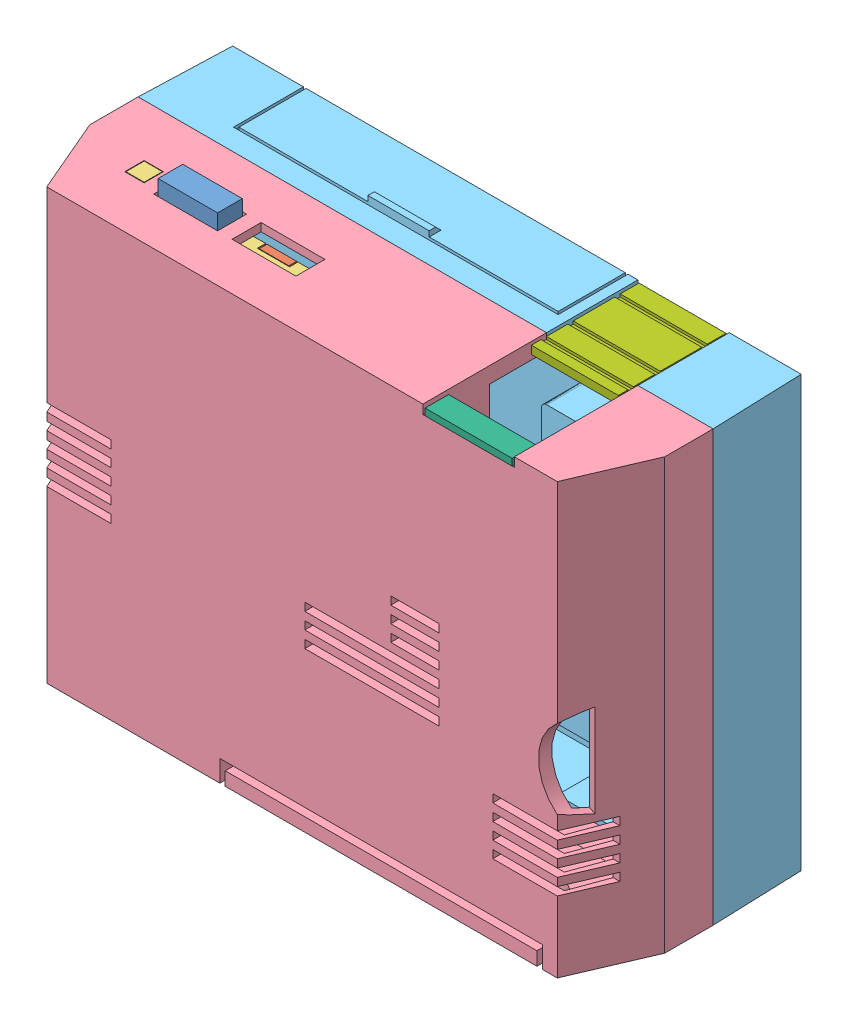
SolidWorks assembly NES_Case_Assembly, configuration Default. Lengths in mm.
Overall size (107 82.5 40).
8 component instances, 8 part files, 21 mates.
Components (placement in the parent):
- NES_Button-1: NES_Button [Default] at (-10.9151 -3.3126 23.1035) size (12.88 5 6.4)
- NES_Switch_Back-1: NES_Switch_Back [Default] at (15.7149 -17.9426 11.9035) x (-1 0 0) z (0 0 -1) size (35.58 8.88 18)
- NES_Switch_Holder-1: NES_Switch_Holder [Default] at (-9.9751 -2.3126 29.9035) x (0 -1 0) z (1 0 0) size (14.63 18 35.58)
- NES_bottom-1: NES_bottom [Default] at (19.7831 -80.8126 42.8615) x (1 0 0) z (0 1 0) size (107 25.5 80)
- NES_top-1: NES_top [Default] at (55.3922 -34.2659 -8.5965) x (1 0 0) z (0 -1 0) size (107 17 81)
- NES_Front_lower_Accent-1: NES_Front_lower_Accent [Default] at (48.8749 -1.2626 27.0335) x (0 -1 0) z (-1 0 0) size (1.25 4.37 16.2)
- NES_Front_upper_Accent-1: NES_Front_upper_Accent [Default] at (48.8749 -1.0126 11.6335) x (1 0 0) z (0 1 0) size (16.2 20.03 14.39)
- NES_Rear_Accent-2: NES_Rear_Accent [Default] at (65.0749 -80.6126 -8.5965) x (-1 0 0) z (0 1 0) size (16.2 17 14.77)
Mates (geometry in assembly coordinates):
- Distance2: distance = 0.4 mm anti-aligned: plane of NES_Button-1 through (-10.0151 1.6874 17.6035) normal (-1 0 0); plane of NES_bottom-1 through (-10.4151 -3.8126 17.2035) normal (1 0 0)
- Distance3: distance = 0.4 mm anti-aligned: plane of NES_Button-1 through (1.0649 1.6874 17.6035) normal (0 0 -1); plane of NES_bottom-1 through (-10.4151 -3.8126 17.2035) normal (0 0 1)
- Coincident22: coincident anti-aligned: plane of NES_Button-1 through (-10.9151 -2.3126 23.1035) normal (0 1 0); plane of NES_bottom-1 through (19.7831 -2.3126 42.8615) normal (0 -1 0)
- Coincident24: coincident anti-aligned: plane of NES_Switch_Holder-1 through (15.7149 -2.3126 29.9035) normal (0 0 1); plane of NES_bottom-1 through (71.6849 -79.3126 29.9035) normal (0 0 -1)
- Distance6: distance = 0.1 mm anti-aligned: plane of NES_Switch_Holder-1 through (-16.6151 -0.8126 18.1935) normal (-1 0 0); plane of NES_bottom-1 through (-16.7151 -3.8126 18.1035) normal (1 0 0)
- Coincident28: coincident anti-aligned: plane of NES_Switch_Holder-1 through (15.7149 -2.3126 26.1835) normal (0 1 0); plane of NES_bottom-1 through (19.7831 -2.3126 42.8615) normal (0 -1 0)
- Coincident29: coincident anti-aligned: plane of NES_Switch_Back-1 through (15.7149 -15.4426 11.9035) normal (0 1 0); plane of NES_Switch_Holder-1 through (15.7149 -15.4426 29.9035) normal (0 -1 0)
- Coincident30: coincident aligned: plane of NES_Switch_Back-1 through (15.7149 -15.4426 11.9035) normal (1 0 0); plane of NES_Switch_Holder-1 through (15.7149 -2.3126 29.9035) normal (1 0 0)
- Coincident31: coincident anti-aligned: plane of NES_Switch_Back-1 through (15.7149 -15.4426 29.9035) normal (0 0 1); plane of NES_bottom-1 through (71.6849 -79.3126 29.9035) normal (0 0 -1)
- Coincident32: coincident: point of NES_bottom-1; point of NES_top-1
- Coincident33: coincident: point of NES_bottom-1; point of NES_top-1
- Coincident36: coincident anti-aligned: plane of NES_bottom-1 through (-25.8251 -2.5126 5.9035) normal (0 1 0); plane of NES_Front_lower_Accent-1 through (48.8749 -2.5126 27.0335) normal (0 -1 0)
- Distance8: distance = 0.4 mm anti-aligned: plane of NES_Front_lower_Accent-1 through (65.0749 -2.5126 27.0335) normal (1 0 0); plane of NES_bottom-1 through (65.4749 -2.5126 31.4035) normal (-1 0 0)
- Coincident38: coincident aligned: plane of NES_bottom-1 through (-21.5251 -77.8126 31.4035) normal (0 0 1); plane of NES_Front_lower_Accent-1 through (48.8749 -1.2626 31.4035) normal (0 0 1)
- Coincident39: coincident anti-aligned: plane of NES_top-1 through (65.4749 -8.5426 -6.8965) normal (0 0 -1); plane of NES_Front_upper_Accent-1 through (65.0749 -15.4026 -6.8965) normal (0 0 1)
- Coincident40: coincident anti-aligned: plane of NES_top-1 through (55.3922 -2.5126 -5.5965) normal (0 1 0); plane of NES_Front_upper_Accent-1 through (65.0749 -2.5126 -6.8965) normal (0 -1 0)
- Distance9: distance = 0.4 mm anti-aligned: plane of NES_Front_upper_Accent-1 through (65.0749 -1.0126 11.6335) normal (1 0 0); plane of NES_top-1 through (65.4749 -34.2659 -5.5965) normal (-1 0 0)
- Coincident42: coincident: point of NES_bottom-1; point of NES_top-1
- Coincident43: coincident anti-aligned: plane of NES_top-1 through (55.3922 -34.2659 -7.0965) normal (0 0 -1); plane of NES_Rear_Accent-2 through (48.8749 -80.6126 -7.0965) normal (0 0 1)
- Coincident44: coincident anti-aligned: plane of NES_top-1 through (55.3922 -79.1126 -5.5965) normal (0 -1 0); plane of NES_Rear_Accent-2 through (48.8749 -79.1126 -8.5965) normal (0 1 0)
- Distance10: distance = 0.4 mm anti-aligned: plane of NES_Rear_Accent-2 through (65.0749 -80.6126 -8.5965) normal (1 0 0); plane of NES_top-1 through (65.4749 -34.2659 -5.5965) normal (-1 0 0)
